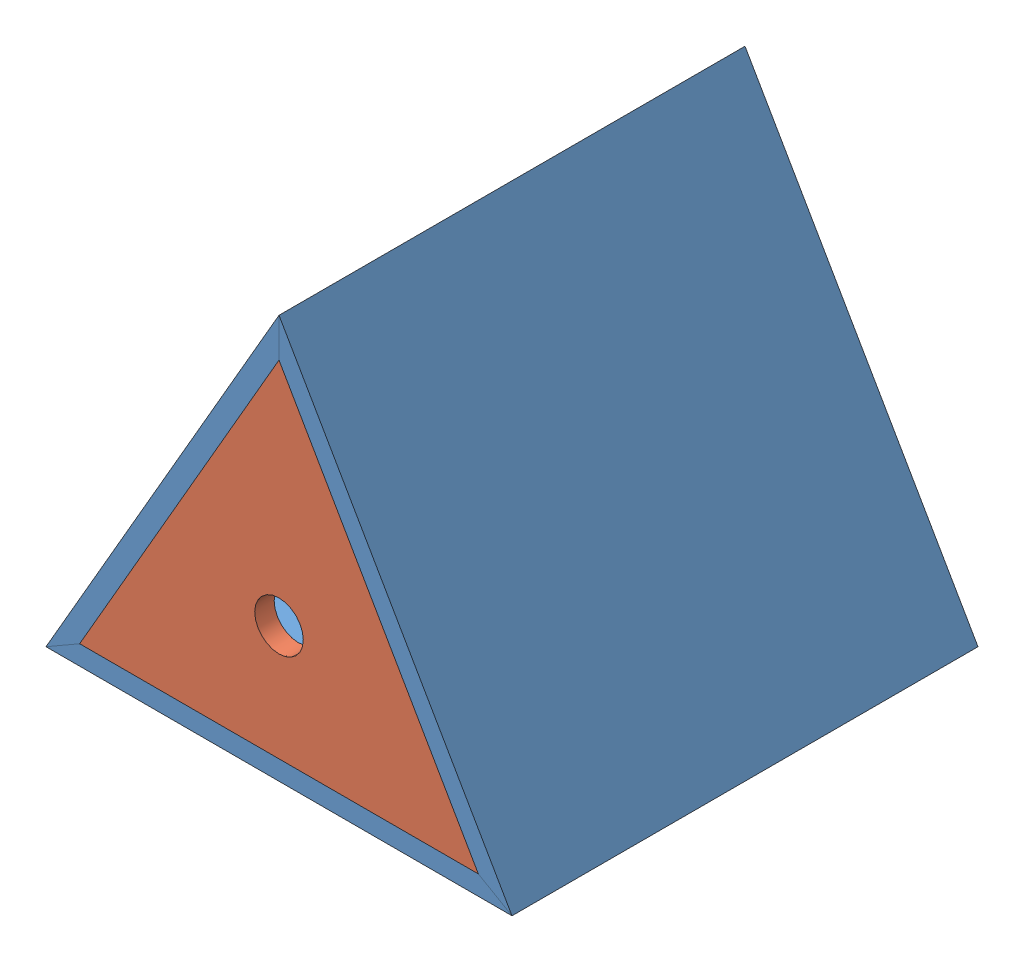
SolidWorks assembly triangle, configuration Default. Lengths in mm.
Overall size (348 364.2 304.8).
11 component instances, 3 part files, 29 mates.
Components (placement in the parent):
- triangle_face-1: triangle_face [Default] at (-35.0317 268.0353 238.4474) size (304.8 12.7 304.8)
- triangle_face-2: triangle_face [Default] at (117.3683 531.9998 238.4474) x (-0.5 -0.866025 0) z (0 0 1) size (304.8 12.7 304.8)
- triangle_face-3: triangle_face [Default] at (269.7683 268.0353 238.4474) x (-0.5 0.866025 0) z (0 0 1) size (304.8 12.7 304.8)
- triangle_top_bot-1: triangle_top_bot [Default] at (269.7683 268.0353 238.4474) x (0.5 -0.866025 0) z (0 0 -1) size (260.81 225.86 12.7)
- triangle_top_bot-2: triangle_top_bot [Default] at (269.7683 268.0353 543.2474) size (260.81 225.86 12.7)
- triangle_inside_corner-1: triangle_inside_corner [Default] at (53.355 472.7151 492.4474) x (0.5 -0.866025 0) z (-0.866025 -0.5 0) size (83.58 38.1 72.38)
- triangle_inside_corner-2: triangle_inside_corner [Default] at (48.317 242.2404 492.4474) x (0.5 0.866025 0) z (0.866025 -0.5 0) size (83.58 38.1 72.38)
- triangle_inside_corner-3: triangle_inside_corner [Default] at (225.5462 242.2404 492.4474) x (0.5 0.866025 0) z (0.866025 -0.5 0) size (83.58 38.1 72.38)
- triangle_inside_corner-4: triangle_inside_corner [Default] at (48.317 242.2404 251.1474) x (0.5 0.866025 0) z (0.866025 -0.5 0) size (83.58 38.1 72.38)
- triangle_inside_corner-6: triangle_inside_corner [Default] at (225.5462 242.2404 251.1474) x (0.5 0.866025 0) z (0.866025 -0.5 0) size (83.58 38.1 72.38)
- triangle_inside_corner-7: triangle_inside_corner [Default] at (53.355 472.7151 251.1474) x (0.5 -0.866025 0) z (-0.866025 -0.5 0) size (83.58 38.1 72.38)
Mates (geometry in assembly coordinates):
- Coincident1: coincident anti-aligned: plane of triangle_face-1 through (-35.0317 268.0353 238.4474) normal (-0.5 0.866025 0); plane of triangle_face-2 through (-35.0317 268.0353 238.4474) normal (0.5 -0.866025 0)
- Coincident2: coincident anti-aligned: line of triangle_face-1 through (-35.0317 268.0353 238.4474) axis (0 0 1); line of triangle_face-2 through (-35.0317 268.0353 543.2474) axis (0 0 -1)
- Coincident3: coincident aligned: plane of triangle_face-1 through (-35.0317 280.7353 543.2474) normal (0 0 1); plane of triangle_face-2 through (128.3668 525.6498 543.2474) normal (0 0 1)
- Coincident4: coincident anti-aligned: plane of triangle_face-1 through (269.7683 268.0353 238.4474) normal (0.5 0.866025 0); plane of triangle_face-3 through (269.7683 268.0353 238.4474) normal (-0.5 -0.866025 0)
- Coincident5: coincident aligned: plane of triangle_face-2 through (128.3668 525.6498 543.2474) normal (0 0 1); plane of triangle_face-3 through (258.7698 261.6853 543.2474) normal (0 0 1)
- Coincident6: coincident anti-aligned: line of triangle_face-1 through (269.7683 268.0353 543.2474) axis (0 0 -1); line of triangle_face-3 through (269.7683 268.0353 238.4474) axis (0 0 1)
- InPlace1: in place: plane of triangle_face-3 through (258.7698 261.6853 238.4474) normal (0 0 -1); plane of ? through (0 0 238.4474) normal (0 0 -1); moOrthogonalPlaneRef_w of triangle_face-3 through (258.7698 261.6853 238.4474) normal (0 0 -1); plane of ? through (0 0 238.4474) normal (0 1 0); plane of triangle_face-3 through (258.7698 261.6853 238.4474) normal (0 0 -1); plane of ? through (0 0 238.4474) normal (-1 0 0); plane of triangle_face-3 through (258.7698 261.6853 238.4474) normal (0 0 -1); unknown of triangle_top_bot-1
- Coincident7: coincident aligned: plane of triangle_face-3; plane of triangle_top_bot-1
- Coincident8: coincident aligned: moOrthogonalPlaneRef_w of triangle_face-3 through (269.7683 268.0353 238.4474) normal (-0.866025 -0.5 0); plane of triangle_top_bot-1 through (269.7683 268.0353 238.4474) normal (-0.866025 -0.5 0)
- Coincident9: coincident anti-aligned: moOrthogonalPlaneRef_w of triangle_face-3 through (269.7683 268.0353 238.4474) normal (-0.5 0.866025 0); plane of triangle_top_bot-1 through (269.7683 268.0353 238.4474) normal (0.5 -0.866025 0)
- Coincident10: coincident aligned: plane of triangle_face-3 through (258.7698 261.6853 238.4474) normal (0 0 -1); plane of triangle_top_bot-1 through (269.7683 268.0353 238.4474) normal (0 0 -1)
- Coincident11: coincident aligned: plane of triangle_face-1 through (-35.0317 280.7353 543.2474) normal (0 0 1); plane of triangle_top_bot-2 through (269.7683 268.0353 543.2474) normal (0 0 1)
- Coincident12: coincident aligned: line of triangle_face-2 through (117.3683 506.5998 543.2474) axis (-0.5 -0.866025 0); line of triangle_top_bot-2 through (117.3683 506.5998 543.2474) axis (-0.5 -0.866025 0)
- Coincident13: coincident aligned: line of triangle_face-3 through (247.7712 280.7353 543.2474) axis (-0.5 0.866025 0); line of triangle_top_bot-2 through (247.7712 280.7353 543.2474) axis (-0.5 0.866025 0)
- Coincident14: coincident anti-aligned: plane of triangle_face-1 through (-35.0317 280.7353 238.4474) normal (0 1 0); plane of triangle_inside_corner-3 through (247.7712 280.7353 530.5474) normal (0 -1 0)
- Coincident15: coincident aligned: line of triangle_face-1 through (-13.0347 280.7353 530.5474) axis (1 0 0); line of triangle_inside_corner-3 through (164.1946 280.7353 530.5474) axis (1 0 0)
- Coincident16: coincident: point of triangle_face-1; point of triangle_inside_corner-3
- Coincident17: coincident aligned: line of triangle_face-1 through (-13.0347 280.7353 530.5474) axis (1 0 0); line of triangle_inside_corner-2 through (-13.0347 280.7353 530.5474) axis (1 0 0)
- Coincident18: coincident: point of triangle_face-1; point of triangle_inside_corner-2
- Coincident19: coincident aligned: line of triangle_face-2 through (117.3683 506.5998 530.5474) axis (-0.5 -0.866025 0); line of triangle_inside_corner-2 through (28.7536 353.1148 530.5474) axis (-0.5 -0.866025 0)
- Coincident23: coincident aligned: line of triangle_face-3 through (247.7712 280.7353 530.5474) axis (-0.5 0.866025 0); line of triangle_inside_corner-1 through (159.1566 434.2203 530.5474) axis (-0.5 0.866025 0)
- Coincident24: coincident aligned: line of triangle_face-2 through (117.3683 506.5998 530.5474) axis (-0.5 -0.866025 0); line of triangle_inside_corner-1 through (117.3683 506.5998 530.5474) axis (-0.5 -0.866025 0)
- Coincident26: coincident aligned: line of triangle_face-1 through (-13.0347 280.7353 251.1474) axis (1 0 0); line of triangle_inside_corner-4 through (-13.0347 280.7353 251.1474) axis (1 0 0)
- Coincident27: coincident aligned: line of triangle_face-2 through (117.3683 506.5998 251.1474) axis (-0.5 -0.866025 0); line of triangle_inside_corner-4 through (28.7536 353.1148 251.1474) axis (-0.5 -0.866025 0)
- Coincident28: coincident aligned: line of triangle_face-3 through (247.7712 280.7353 251.1474) axis (-0.5 0.866025 0); line of triangle_inside_corner-5 through (-41709.6807 72953.1738 251.1474) axis (-0.5 0.866025 0)
- Coincident29: coincident aligned: line of triangle_face-3 through (247.7712 280.7353 251.1474) axis (-0.5 0.866025 0); line of triangle_inside_corner-6 through (247.7712 280.7353 251.1474) axis (-0.5 0.866025 0)
- Coincident30: coincident aligned: line of triangle_face-1 through (-13.0347 280.7353 251.1474) axis (1 0 0); line of triangle_inside_corner-6 through (164.1946 280.7353 251.1474) axis (1 0 0)
- Coincident31: coincident aligned: line of triangle_face-3 through (247.7712 280.7353 251.1474) axis (-0.5 0.866025 0); line of triangle_inside_corner-7 through (159.1566 434.2203 251.1474) axis (-0.5 0.866025 0)
- Coincident32: coincident aligned: line of triangle_face-2 through (117.3683 506.5998 251.1474) axis (-0.5 -0.866025 0); line of triangle_inside_corner-7 through (117.3683 506.5998 251.1474) axis (-0.5 -0.866025 0)
